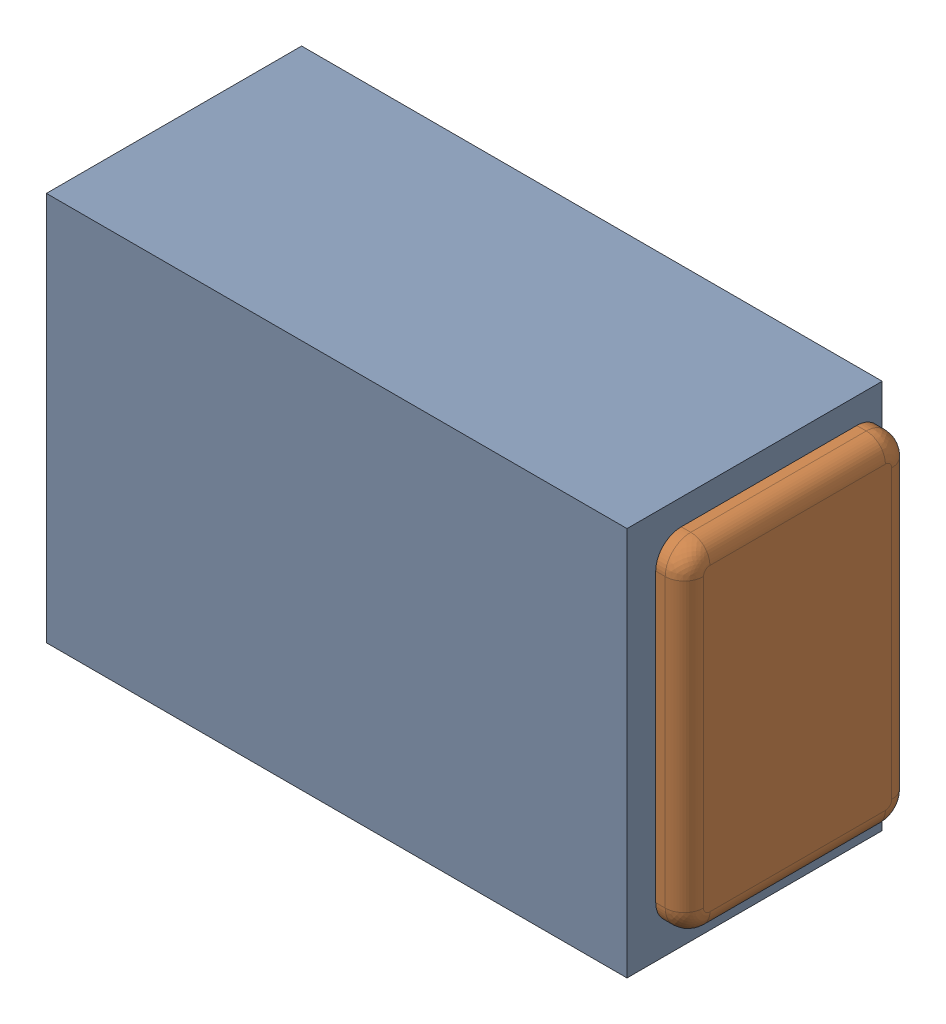
SolidWorks assembly C4, configuration Default. Lengths in mm.
Overall size (1 0.61 0.4).
3 component instances, 2 part files, 0 mates.
Components (placement in the parent):
- 1088880352-1: 1088880352 [Default] at (7.65 40.9 0) size (0.91 0.61 0.4)
  - Extruded-28-1: Extruded-28 [Default] at origin size (0.91 0.61 0.4)
- C0402-1: C0402 [Default] at (7.6499 40.8999 0) x (-1 0 0) z (0 1 0) size (1 0.36 0.54)
